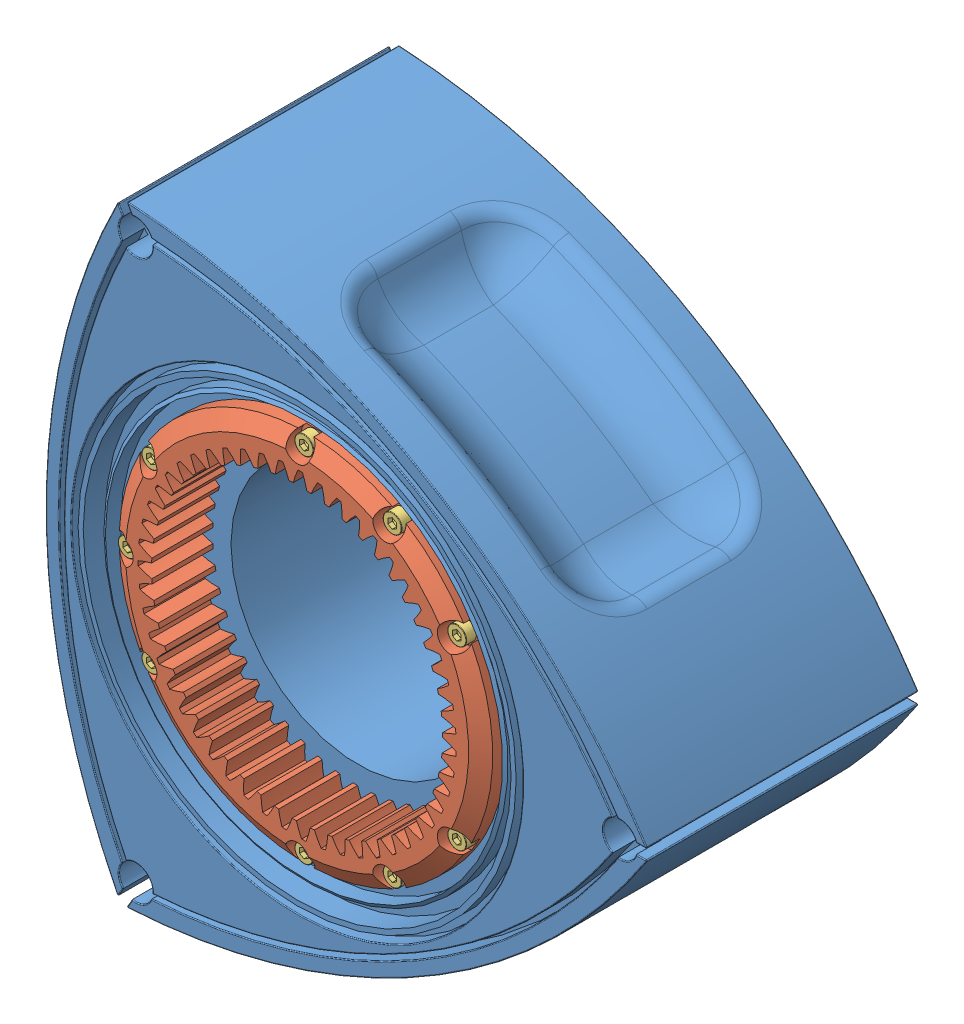
SolidWorks assembly Rotor W, configuration Default. Lengths in mm.
Overall size (178.74 179.93 80.05).
11 component instances, 3 part files, 20 mates.
Components (placement in the parent):
- Core-2: Core [Predeterminado] at origin size (178.74 179.93 80.05)
- internal spur gear_iso-2: internal spur gear_iso [ISO - Internal spur gear 1.75M 51T 14.5PA 18FW ---S51S110OD 1.0AF] at (0 0 62) x (0 0 1) z (0.407698 0.913117 0) size (18 110 110)
- socket head cap screw_iso-1: socket head cap screw_iso [ISO 4762 M3 x 30 - 18N] at (26 45.0333 78) x (0 0 -1) z (1 0 0) size (33 5.5 5.5)
- socket head cap screw_iso-2: socket head cap screw_iso [ISO 4762 M3 x 30 - 18N] at (0 52 78) x (0 0 -1) z (1 0 0) size (33 5.5 5.5)
- socket head cap screw_iso-3: socket head cap screw_iso [ISO 4762 M3 x 30 - 18N] at (-45.0333 26 78) x (0 0 -1) z (1 0 0) size (33 5.5 5.5)
- socket head cap screw_iso-4: socket head cap screw_iso [ISO 4762 M3 x 30 - 18N] at (-52 0 78) x (0 0 -1) z (1 0 0) size (33 5.5 5.5)
- socket head cap screw_iso-5: socket head cap screw_iso [ISO 4762 M3 x 30 - 18N] at (-45.0333 -26 78) x (0 0 -1) z (1 0 0) size (33 5.5 5.5)
- socket head cap screw_iso-6: socket head cap screw_iso [ISO 4762 M3 x 30 - 18N] at (0 -52 78) x (0 0 -1) z (1 0 0) size (33 5.5 5.5)
- socket head cap screw_iso-7: socket head cap screw_iso [ISO 4762 M3 x 30 - 18N] at (26 -45.0333 78) x (0 0 -1) z (1 0 0) size (33 5.5 5.5)
- socket head cap screw_iso-8: socket head cap screw_iso [ISO 4762 M3 x 30 - 18N] at (45.0333 -26 78) x (0 0 -1) z (1 0 0) size (33 5.5 5.5)
- socket head cap screw_iso-9: socket head cap screw_iso [ISO 4762 M3 x 30 - 18N] at (45.0333 26 78) x (0 0 -1) z (1 0 0) size (33 5.5 5.5)
Mates (geometry in assembly coordinates):
- Concéntrica2: concentric: cylinder of Core-2 through (0 0 0) axis (0 0 -1) radius 58.5; cylinder of internal spur gear_iso-2 through (0 0 52) axis (0 0 -1) radius 55
- Coincidente4: coincident: plane of Core-2 through (-55 0 62) normal (0 0 1); plane of internal spur gear_iso-2 through (-17.48 -39.1499 62) normal (0 0 -1)
- Concéntrica31: concentric: cylinder of internal spur gear_iso-2 through (26 45.0333 80) axis (0 0 1) radius 1.7; cylinder of socket head cap screw_iso-1 through (26 45.0333 109.75) axis (0 0 1) radius 1.5
- Coincidente51: coincident: plane of internal spur gear_iso-2 through (27.7 45.0333 75) normal (0 0 1); plane of socket head cap screw_iso-1 through (26 47.7833 75) normal (0 0 -1)
- Concéntrica41: concentric: cylinder of internal spur gear_iso-2 through (0 52 80) axis (0 0 1) radius 1.7; cylinder of socket head cap screw_iso-2 through (0 52 109.75) axis (0 0 1) radius 1.5
- Coincidente61: coincident: plane of internal spur gear_iso-2 through (1.7 52 75) normal (0 0 1); plane of socket head cap screw_iso-2 through (0 54.75 75) normal (0 0 -1)
- Concéntrica51: concentric: cylinder of internal spur gear_iso-2 through (-45.0333 26 80) axis (0 0 1) radius 1.7; cylinder of socket head cap screw_iso-3 through (-45.0333 26 109.75) axis (0 0 1) radius 1.5
- Coincidente71: coincident: plane of internal spur gear_iso-2 through (-43.3333 26 75) normal (0 0 1); plane of socket head cap screw_iso-3 through (-45.0333 28.75 75) normal (0 0 -1)
- Concéntrica61: concentric: cylinder of internal spur gear_iso-2 through (-52 0 80) axis (0 0 1) radius 1.7; cylinder of socket head cap screw_iso-4 through (-52 0 109.75) axis (0 0 1) radius 1.5
- Coincidente81: coincident: plane of internal spur gear_iso-2 through (-50.3 0 75) normal (0 0 1); plane of socket head cap screw_iso-4 through (-52 2.75 75) normal (0 0 -1)
- Concéntrica71: concentric: cylinder of internal spur gear_iso-2 through (-45.0333 -26 80) axis (0 0 1) radius 1.7; cylinder of socket head cap screw_iso-5 through (-45.0333 -26 109.75) axis (0 0 1) radius 1.5
- Coincidente91: coincident: plane of internal spur gear_iso-2 through (-43.3333 -26 75) normal (0 0 1); plane of socket head cap screw_iso-5 through (-45.0333 -23.25 75) normal (0 0 -1)
- Concéntrica81: concentric: cylinder of internal spur gear_iso-2 through (0 -52 80) axis (0 0 1) radius 1.7; cylinder of socket head cap screw_iso-6 through (0 -52 109.75) axis (0 0 1) radius 1.5
- Coincidente101: coincident: plane of internal spur gear_iso-2 through (1.7 -52 75) normal (0 0 1); plane of socket head cap screw_iso-6 through (0 -49.25 75) normal (0 0 -1)
- Concéntrica91: concentric: cylinder of internal spur gear_iso-2 through (26 -45.0333 80) axis (0 0 1) radius 1.7; cylinder of socket head cap screw_iso-7 through (26 -45.0333 109.75) axis (0 0 1) radius 1.5
- Coincidente111: coincident: plane of internal spur gear_iso-2 through (27.7 -45.0333 75) normal (0 0 1); plane of socket head cap screw_iso-7 through (26 -42.2833 75) normal (0 0 -1)
- Concéntrica101: concentric: cylinder of internal spur gear_iso-2 through (45.0333 -26 80) axis (0 0 1) radius 1.7; cylinder of socket head cap screw_iso-8 through (45.0333 -26 109.75) axis (0 0 1) radius 1.5
- Coincidente121: coincident: plane of internal spur gear_iso-2 through (46.7333 -26 75) normal (0 0 1); plane of socket head cap screw_iso-8 through (45.0333 -23.25 75) normal (0 0 -1)
- Concéntrica111: concentric: cylinder of internal spur gear_iso-2 through (45.0333 26 80) axis (0 0 1) radius 1.7; cylinder of socket head cap screw_iso-9 through (45.0333 26 109.75) axis (0 0 1) radius 1.5
- Coincidente131: coincident: plane of internal spur gear_iso-2 through (46.7333 26 75) normal (0 0 1); plane of socket head cap screw_iso-9 through (45.0333 28.75 75) normal (0 0 -1)
